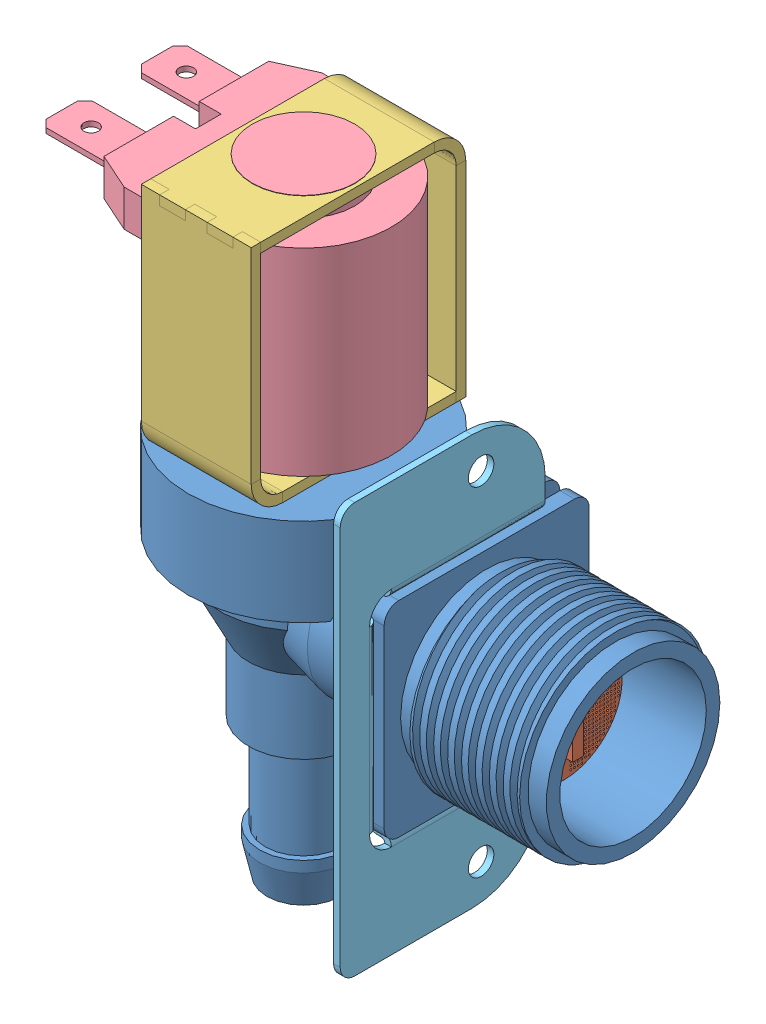
SolidWorks assembly Solenoid valve _ 3 over 4 Inch, configuration Default. Lengths in mm.
Overall size (71.5 85.35 35.15).
6 component instances, 5 part files, 17 mates.
Components (placement in the parent):
- solenoid valve-1: solenoid valve [Default] at origin size (60.75 53 31.5)
- Water Filter-1: Water Filter [Default] at (28 37 0) x (0 0 1) z (0 1 0) size (16 9.5 16)
- sheet metal part-1: sheet metal part [Default] at (7.5 54.3 13.35) x (0 0 -1) z (1 0 0) size (29.3 32.3 15)
- sheet metal part-2: sheet metal part [Default] at (7.5 84 -13.35) x (0 0 1) z (1 0 0) size (29.3 32.3 15)
- solenoid-1: solenoid [Default] at (0 55.65 0) x (-1 0 0) z (0 0 -1) size (38.5 32.4 27)
- Fixer-1: Fixer [Default] at (24.4 37 5.4) x (0 1 0) z (1 0 0) size (56 28 3.4)
Mates (geometry in assembly coordinates):
- Concentric1: concentric anti-aligned: cylinder of solenoid valve-1 through (28 37 0) axis (1 0 0) radius 10; cylinder of Water Filter-1 through (28 37 0) axis (-1 0 0) radius 8
- Coincident1: coincident anti-aligned: plane of solenoid valve-1 through (28 37 0) normal (1 0 0); plane of Water Filter-1 through (28 29 0) normal (-1 0 0)
- Parallel1: parallel anti-aligned: plane of Water Filter-1 through (35.5 41.5 -0.75) normal (0 0 -1); plane of assembly through (0 0 0) normal (0 0 1)
- Concentric2: concentric anti-aligned: cylinder of solenoid valve-1 through (0 0 0) axis (0 -1 0) radius 15.75; circle of sheet metal part-1
- Coincident3: coincident anti-aligned: plane of solenoid valve-1 through (15.75 53 0) normal (0 1 0); plane of sheet metal part-1 through (-7.5 53 13.35) normal (0 -1 0)
- Parallel2: parallel aligned: plane of sheet metal part-1 through (-7.5 54.3 14.65) normal (0 0 1); plane of assembly through (0 0 0) normal (0 0 1)
- Coincident5: coincident anti-aligned: plane of sheet metal part-1 through (1.5 84 4.65) normal (0 1 0); plane of sheet metal part-2 through (-7.5 84 -13.35) normal (0 -1 0)
- Coincident6: coincident anti-aligned: plane of sheet metal part-1 through (-5 85.3 4.65) normal (1 0 0); plane of sheet metal part-2 through (-5 75.3 14.65) normal (-1 0 0)
- Coincident7: coincident aligned: plane of sheet metal part-1 through (-7.5 54.3 14.65) normal (0 0 1); plane of sheet metal part-2 through (-7.5 84 14.65) normal (0 0 1)
- Concentric3: concentric aligned: cylinder of solenoid valve-1 through (0 0 0) axis (0 -1 0) radius 15.75; cylinder of solenoid-1 through (0 55.65 0) axis (0 -1 0) radius 12
- Coincident9: coincident anti-aligned: plane of solenoid-1 through (0 55.65 0) normal (0 0 -1); plane of assembly through (0 0 0) normal (0 0 1)
- Width1: width aligned: plane of solenoid-1 through (-7 82.65 0) normal (0 1 0); plane of solenoid-1 through (-12 55.65 0) normal (0 -1 0); plane of sheet metal part-1 through (-7.5 54.3 13.35) normal (0 1 0); plane of sheet metal part-2 through (-7.5 84 -13.35) normal (0 -1 0)
- Parallel6: parallel aligned: plane of Fixer-1 through (24.4 63 17.4) normal (1 0 0); plane of assembly through (0 0 0) normal (1 0 0)
- Parallel3: parallel aligned: plane of Fixer-1; plane of assembly through (0 0 0) normal (0 0 1)
- Tangent1: tangent anti-aligned: cylinder of solenoid valve-1 through (0 37 0) axis (-1 0 0) radius 11.75; plane of Fixer-1 through (21 25.25 -8.6) normal (0 1 0)
- Coincident15: coincident anti-aligned: plane of solenoid valve-1 through (21 49 -12) normal (1 0 0); plane of Fixer-1 through (21 37 5.4) normal (-1 0 0)
- Coincident16: coincident: plane of solenoid valve-1 through (23 25 14) normal (0 0 1); line of Fixer-1 through (23 24.75 14) axis (0 1 0)
